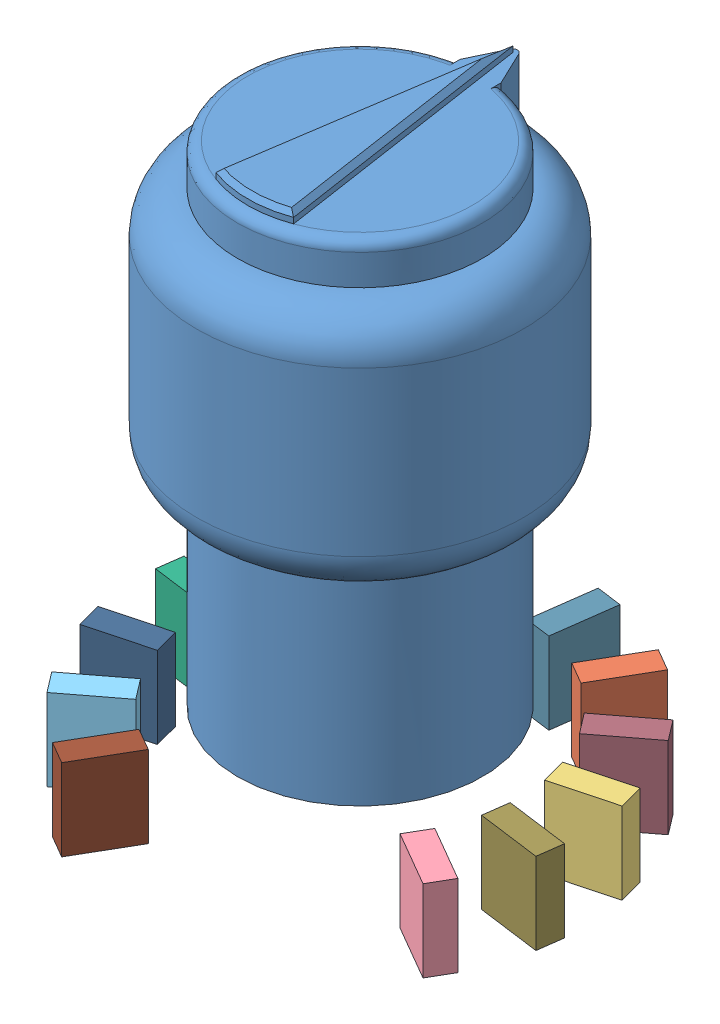
SolidWorks assembly Baugruppe4, configuration Standard. Lengths in mm.
Overall size (20.51 22.62 18.99).
15 component instances, 14 part files, 2 mates.
Components (placement in the parent):
- Big-Knob-1: Big-Knob [Standard] at (-9.1243 -7.6351 19.4469) size (12.7 19.45 12.7)
- Big-Knob-Leds-1: Big-Knob-Leds [Standard] at (-9.1243 -10.8101 19.4469) x (0.966513 0 -0.256616) z (0 1 0) size (17.24 15.07 3.17)
  - Big-Knob-Led-9-1: Big-Knob-Led-9 [Standard] at origin size (2.44 2.44 3.17)
  - Big-Knob-Led-11-1: Big-Knob-Led-11 [Standard] at origin size (2.46 0.99 3.17)
  - Big-Knob-Led-13-1: Big-Knob-Led-13 [Standard] at origin size (2.44 2.44 3.17)
  - Big-Knob-Led-2-1: Big-Knob-Led-2 [Standard] at origin size (2.66 1.86 3.17)
  - Big-Knob-Led-4-1: Big-Knob-Led-4 [Standard] at origin size (2.66 1.86 3.17)
  - Big-Knob-Led-6-1: Big-Knob-Led-6 [Standard] at origin size (1.86 2.66 3.17)
  - Big-Knob-Led-7-1: Big-Knob-Led-7 [Standard] at origin size (0.99 2.46 3.17)
  - Big-Knob-Led-5-1: Big-Knob-Led-5 [Standard] at origin size (2.44 2.44 3.17)
  - Big-Knob-Led-3-1: Big-Knob-Led-3 [Standard] at origin size (2.46 0.99 3.17)
  - Big-Knob-Led-1-1: Big-Knob-Led-1 [Standard] at origin size (2.44 2.44 3.17)
  - Big-Knob-Led-12-1: Big-Knob-Led-12 [Standard] at origin size (2.66 1.86 3.17)
  - Big-Knob-Led-10-1: Big-Knob-Led-10 [Standard] at origin size (2.66 1.86 3.17)
  - Big-Knob-Led-8-1: Big-Knob-Led-8 [Standard] at origin size (1.86 2.66 3.17)
Mates (geometry in assembly coordinates):
- Konzentrisch1: concentric aligned: circle of Big-Knob-1; line of ? through (-9.1243 -10.8101 19.4469) axis (0 1 0)
- Deckungsgleich1: coincident anti-aligned: plane of Big-Knob-1 through (-9.1243 -7.6351 19.4469) normal (0 -1 0); plane of ? through (-2.7338 -7.6351 23.1558) normal (0 1 0)
